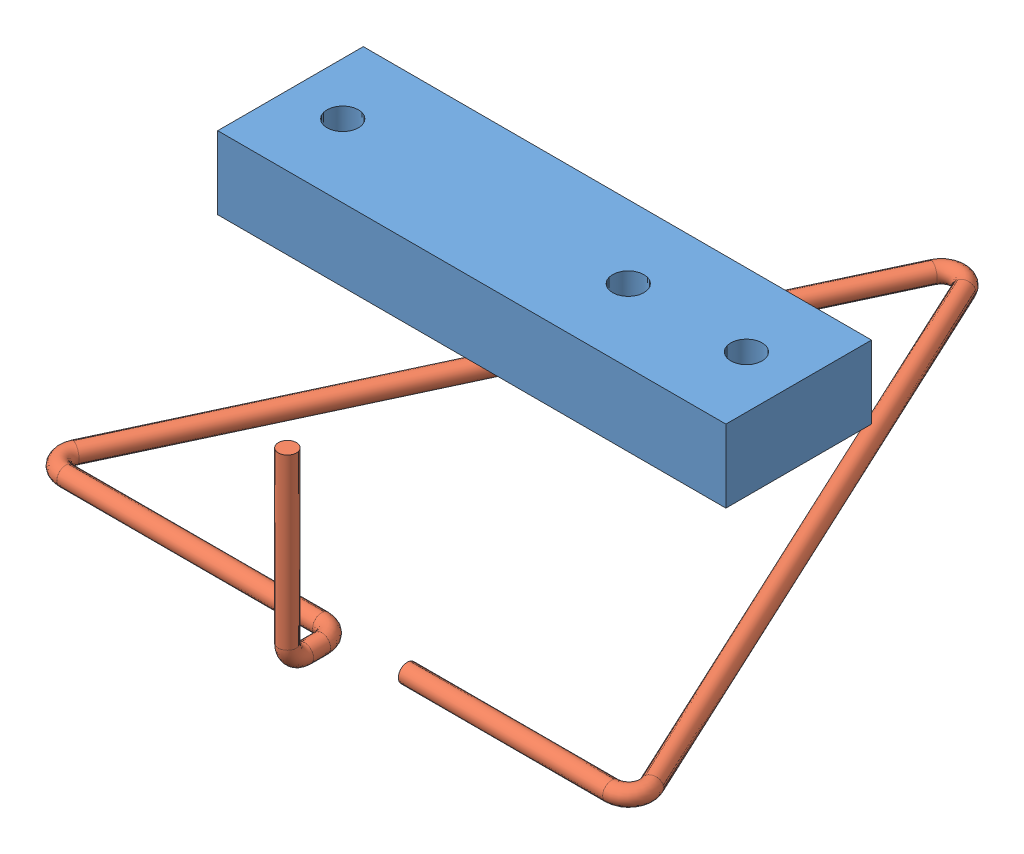
SolidWorks assembly Montagem1, configuration Valor predeterminado. Lengths in mm.
Overall size (104.75 46.93 120.66).
2 component instances, 2 part files, 1 mates.
Components (placement in the parent):
- Suporte Arames-1: Suporte Arames [Valor predeterminado] at (41.7157 -6.8855 101.75) size (89 12.75 25.5)
- Triangulo-1: Triangulo [Valor predeterminado] at (-5.8467 -39.4855 126.4826) size (104.75 34.19 120.66)
Mates (geometry in assembly coordinates):
- Coincidente3: coincident: plane of assembly; circle of assembly; plane of Suporte Arames-1 through (41.7157 -6.8855 101.75) normal (0 -1 0); circle of Triangulo-1
